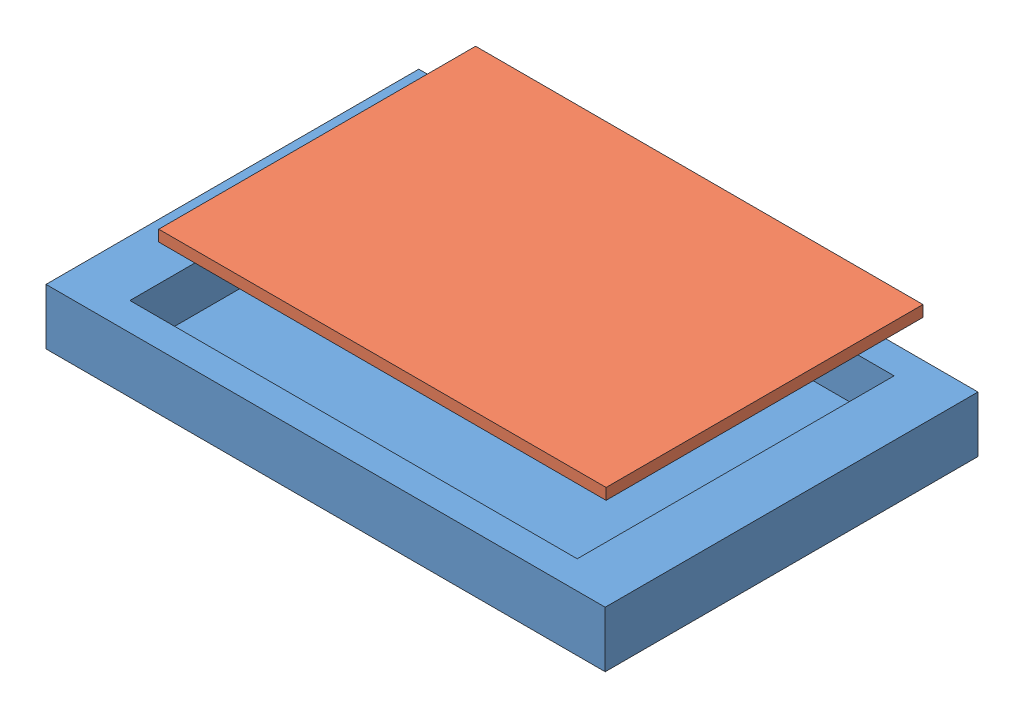
SolidWorks assembly МакетА, configuration По умолчанию. Lengths in mm.
Overall size (150 29.21 100).
2 component instances, 2 part files, 0 mates.
Components (placement in the parent):
- КорпусА-1: КорпусА [По умолчанию] at origin size (150 15 100)
- КрышкаА-1: КрышкаА [По умолчанию] at (1.5107 26.2146 -6.2279) size (120 3 85)
